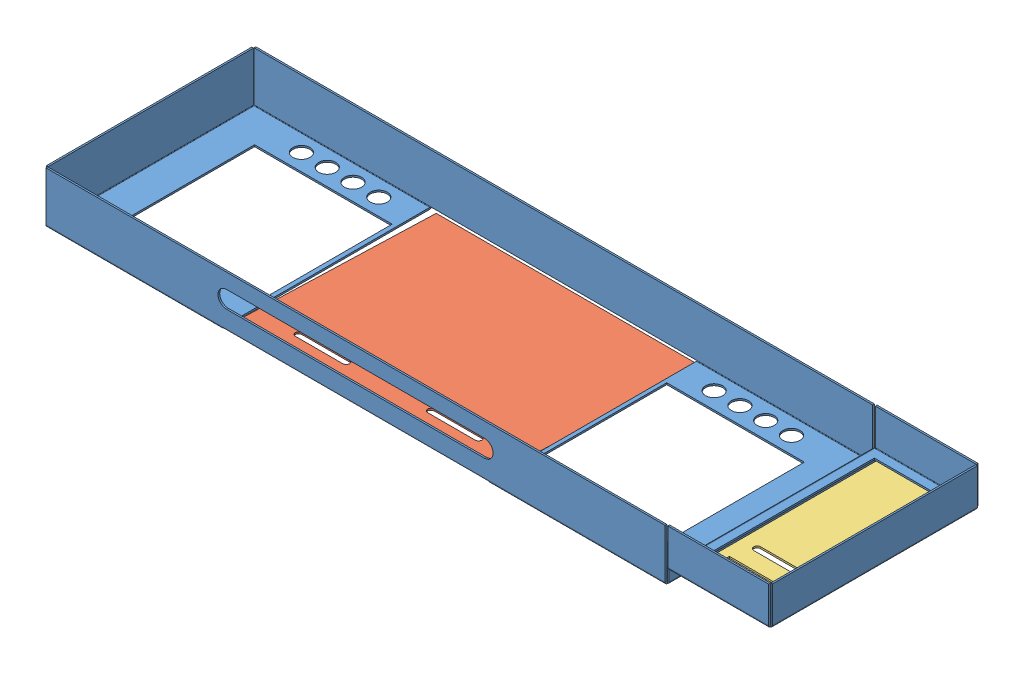
SolidWorks assembly newfangled drive station, configuration Default. Lengths in mm.
Overall size (1071.88 86.49 313.54).
3 component instances, 3 part files, 4 mates.
Components (placement in the parent):
- driverstation-1: driverstation [Default] at (360.5025 377.1991 742.2287) size (1071.88 76.71 309.88)
- Laptop Plate-1: Laptop Plate [Default] at (360.5025 372.594 739.121) x (-1 0 0) z (0 -0.033271 -0.999446) size (388.62 2.54 311.15)
- Button Plate-2: Button Plate [Default] at (894.7915 394.9306 721.7055) x (-1 0 0) z (0 -0.000382 -1) size (118.62 2.54 254)
Mates (geometry in assembly coordinates):
- Coincident13: coincident anti-aligned: line of driverstation-1 through (956.6659 394.9791 848.7055) axis (-1 0 0); line of Button Plate-2 through (940.5115 394.9791 848.7055) axis (1 0 0)
- Distance1: distance = 2.54 mm: plane of Button Plate-2 through (835.4825 392.342 594.7065) normal (-1 0 0); line of driverstation-1 through (832.9425 394.9791 848.7055) axis (0 0 -1)
- Coincident15: coincident aligned: line of driverstation-1 through (163.6525 377.7701 894.6099) axis (1 0 0); line of Laptop Plate-1 through (308.4325 377.7701 894.6099) axis (1 0 0)
- Distance2: distance = 2.54 mm anti-aligned: plane of Laptop Plate-1 through (166.1925 364.8793 583.7166) normal (-1 0 0); plane of driverstation-1 through (163.6525 374.6591 904.7887) normal (1 0 0)
